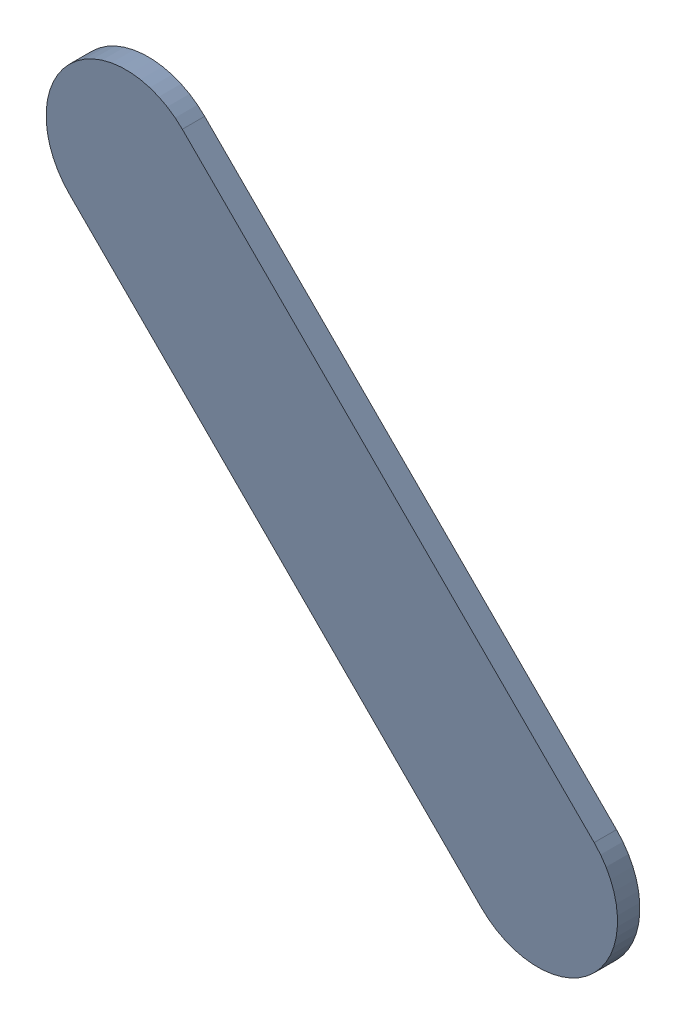
SolidWorks assembly Track (16.7mm,27.749mm)(17.356mm,27.093mm) on Top Layer, configuration Predeterminado. Lengths in mm.
Overall size (0.91 0.91 0.04).
2 component instances, 1 part files, 0 mates.
Components (placement in the parent):
- Track (16.7mm,27.749mm)(17.356mm,27.093mm) on Top Layer-1-1: Track (16.7mm,27.749mm)(17.356mm,27.093mm) on Top Layer-1 [Predeterminado] at (-68.317 -44.187 -0.0457) size (0.91 0.91 0.04)
  - Track (16.7mm,27.749mm)(17.356mm,27.093mm) on Top Layer-Part-1-1: Track (16.7mm,27.749mm)(17.356mm,27.093mm) on Top Layer-Part-1 [Predeterminado] at origin size (0.91 0.91 0.04)
